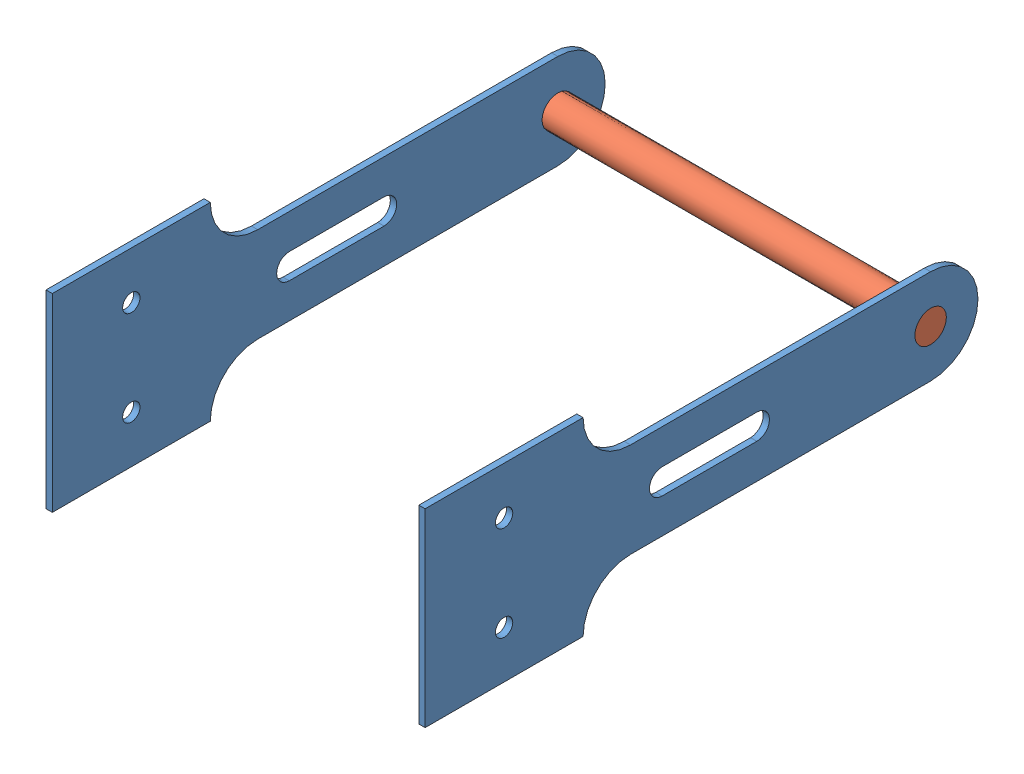
SolidWorks assembly Soporte Armado, configuration Predeterminado. Lengths in mm.
Overall size (240 120 350).
3 component instances, 2 part files, 5 mates.
Components (placement in the parent):
- Soporte-1: Soporte [Predeterminado] at origin size (4 120 350)
- Barra-1: Barra [Predeterminado] at (-236 60 -320) x (0 0 -1) z (1 0 0) size (20 20 240)
- Soporte-2: Soporte [Predeterminado] at (-232 120 0) x (-1 0 0) z (0 0 1) size (4 120 350)
Mates (geometry in assembly coordinates):
- Concéntrica1: concentric anti-aligned: cylinder of Soporte-1 through (0 60 -320) axis (1 0 0) radius 10; cylinder of Barra-1 through (4 60 -320) axis (-1 0 0) radius 10
- Coincidente1: coincident aligned: plane of Soporte-1 through (4 120 -130) normal (1 0 0); plane of Barra-1 through (4 60 -320) normal (1 0 0)
- Concéntrica2: concentric aligned: cylinder of Barra-1 through (4 60 -320) axis (-1 0 0) radius 10; cylinder of Soporte-2 through (-232 60 -320) axis (-1 0 0) radius 10
- Coincidente2: coincident aligned: plane of Barra-1 through (-236 60 -320) normal (-1 0 0); plane of Soporte-2 through (-236 0 -130) normal (-1 0 0)
- Coincidente3: coincident aligned: plane of Soporte-1 through (4 120 0) normal (0 1 0); plane of Soporte-2 through (-236 120 -100) normal (0 1 0)
